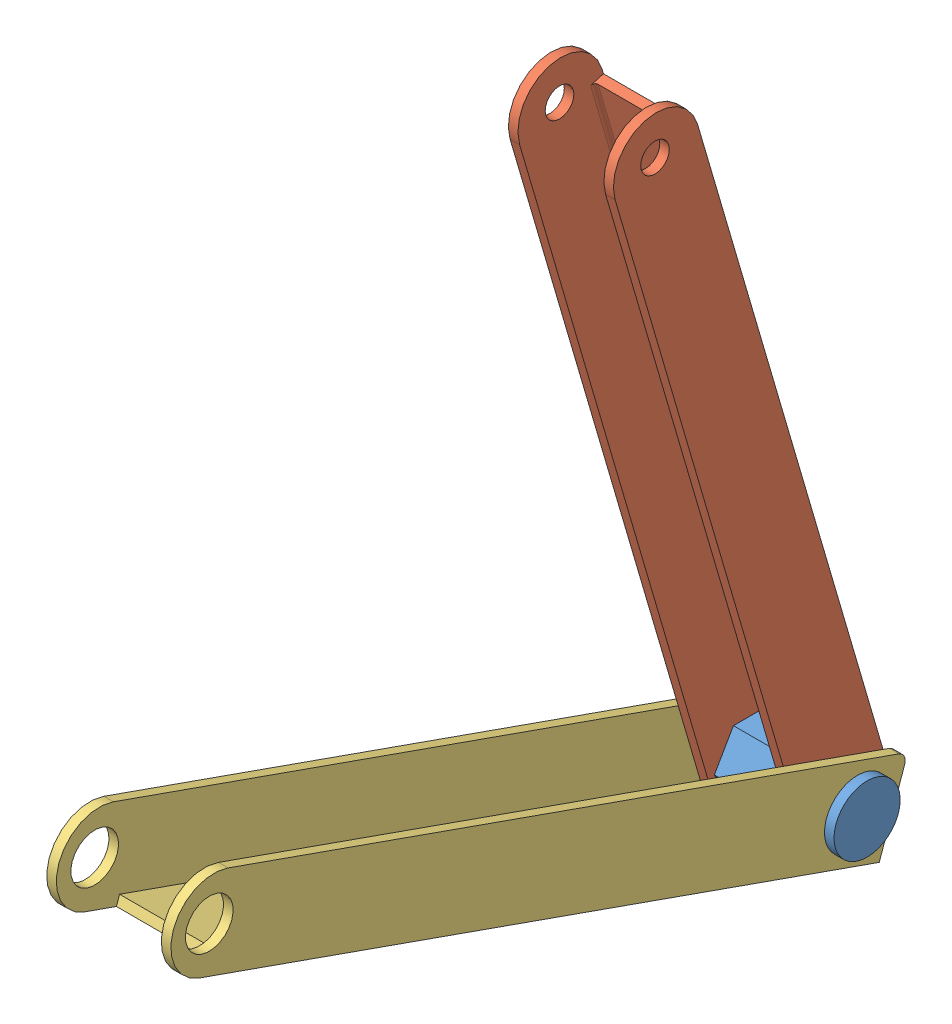
SolidWorks assembly major, configuration Default. Lengths in mm.
Overall size (75 398.91 393.06).
3 component instances, 3 part files, 3 mates.
Components (placement in the parent):
- Pin-1: Pin [Default] at (34.6956 36.1979 56.0316) size (75 34.64 40)
- Arm - Upper-1: Arm - Upper [Default] at (34.6956 213.8718 89.7693) x (0 -0.959783 -0.280744) z (-1 0 0) size (400 45 55)
- Arm - Lower-1: Arm - Lower [Default] at (34.6956 79.5672 231.6031) x (0 0.332627 0.943059) z (-1 0 0) size (400 45 65)
Mates (geometry in assembly coordinates):
- Concentric1: concentric aligned: cylinder of Pin-1 through (72.1956 36.1979 56.0316) axis (-1 0 0) radius 17.3205; circle of Arm - Lower-1
- Distance1: distance = 5 mm aligned: plane of Pin-1 through (72.1956 36.1979 56.0316) normal (1 0 0); plane of Arm - Lower-1 through (67.1956 146.0925 420.2148) normal (1 0 0)
- Concentric2: concentric anti-aligned: circle of Pin-1; circle of Arm - Upper-1
